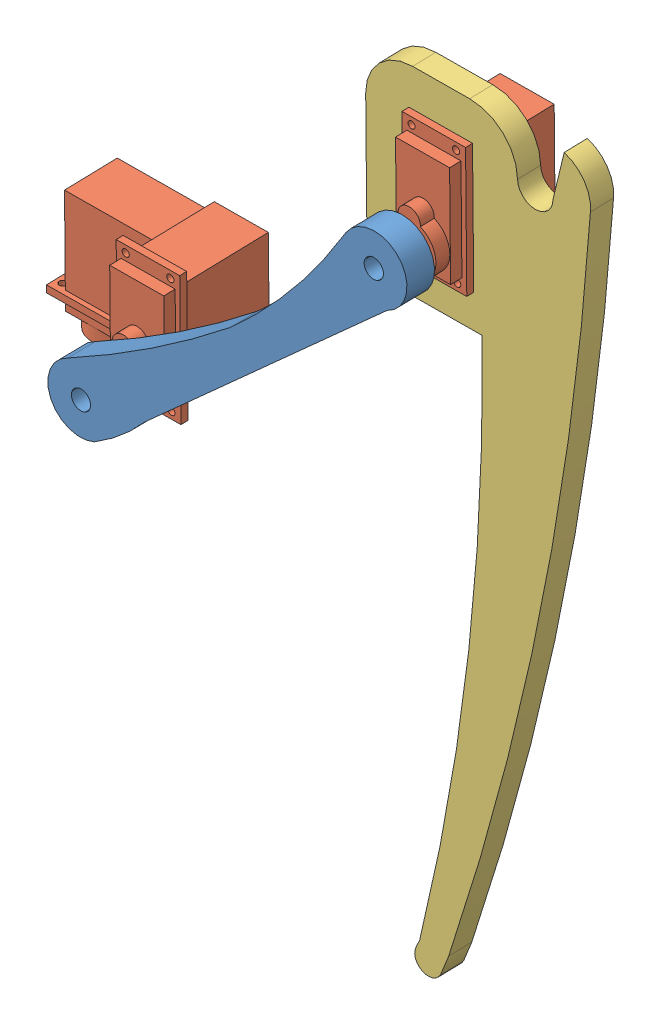
SolidWorks assembly PataCompleteMirrored, configuration Default. Lengths in mm.
Overall size (124.13 169.89 41.15).
7 component instances, 4 part files, 0 mates.
Components (placement in the parent):
- Part3^Assembly-1: Part3^Assembly [Default] at origin (virtual)
- MirrorPataComplete-26: MirrorPataComplete [Default] at (-69.7487 27.9974 -2.3661) x (-0.999912 0.004345 0.012534) z (-0.012472 0.013914 -0.999825) size (122.91 168.85 37.28)
  - MirrorPata2-1: MirrorPata2 [Default] at (-152.6346 -170.0138 -44.9187) x (-0.912683 0.408511 0.011306) z (-0.004803 0.01694 -0.999845) size (91.94 38.8 6)
  - MirrorServo Turningy 9g-1: MirrorServo Turningy 9g [Valor predeterminado] at (-152.6505 -165.0366 -10.1296) x (1 0 0) z (0 1 0) size (13.4 28.6 27.8)
  - MirrorServo Turningy 9g-2: MirrorServo Turningy 9g [Valor predeterminado] at (-213.6482 -110.33 -10.3803) x (1 0 0) z (0 1 0) size (13.4 28.6 27.8)
  - MirrorServo Turningy 9g-3: MirrorServo Turningy 9g [Valor predeterminado] at (-136.0821 -157.6358 -14.5126) x (0 0 -1) z (-1 0 0) size (13.4 28.6 27.8)
  - MirrorPata-1: MirrorPata [Default] at (-207.6364 -98.5483 -23.8802) x (0 1 0) z (0 0 1) size (168.85 47.43 5)
